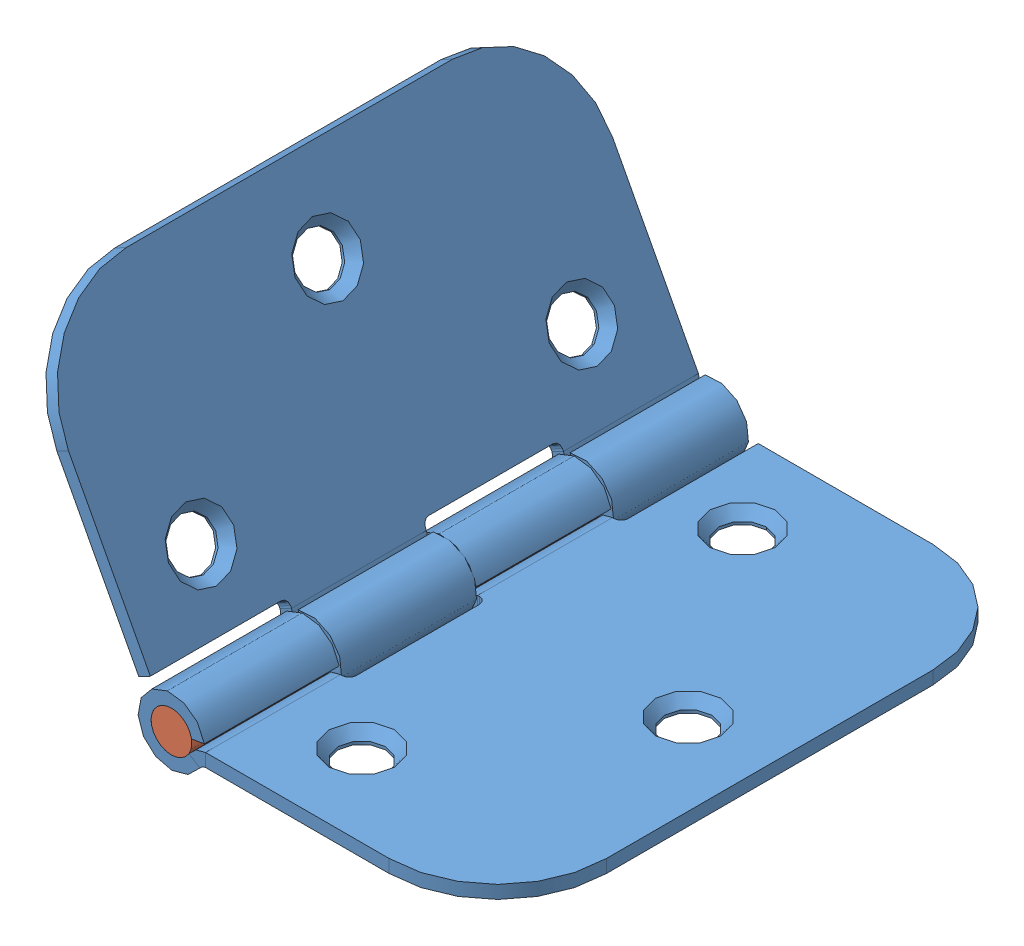
SolidWorks assembly Hinge_01, configuration Default. Lengths in mm.
Overall size (59.41 40.75 63.5).
3 component instances, 2 part files, 6 mates.
Components (placement in the parent):
- Hinge_01-1: Hinge_01 [Default] at origin size (42 7.8 63.5)
- Hinge_01-2: Hinge_01 [Default] at (-56.0759 33.72 -63.5) x (-0.468865 0.88327 0) z (0 0 -1) size (42 7.8 63.5)
- Hinge_01_Pin-1: Hinge_01_Pin [Default] at (-56.0759 33.72 -63.5) x (-0.468865 0.88327 0) z (0 0 -1) size (4.75 4.75 63.5)
Mates (geometry in assembly coordinates):
- Concentric1: concentric anti-aligned: cylinder of Hinge_01-1 through (-38.1 0.127 -127.7853) axis (0 0 1) radius 2.3749; cylinder of Hinge_01-2 through (-38.1 0.127 36.1195) axis (0 0 -1) radius 2.3749
- Coincident1: coincident aligned: plane of Hinge_01-1 through (-34.1123 -144.1652 -63.5) normal (0 0 -1); plane of Hinge_01-2 through (-167.4186 -64.0044 -63.5) normal (0 0 -1)
- Inplace1: in place: line of ? through (-38.1 0.127 -63.5) axis (0 0 -1); line of ? through (-57.6566 32.8251 -63.5) axis (0 0 -1); moOrthogonalPlaneRef_w of ? through (-38.1 0.127 -63.5) axis (0 0 -1); line of ? through (-57.6566 32.8251 -63.5) axis (0.859919 0.510431 0); line of ? through (-38.1 0.127 -63.5) axis (0 0 -1); line of ? through (-57.6566 32.8251 -63.5) axis (-0.510431 0.859919 0); plane of ? through (-38.1 0.127 -63.5) normal (0 0 -1); unknown of ?
- Coincident2: coincident aligned: plane of Hinge_01-2; plane of Hinge_01_Pin-1
- Coincident3: coincident aligned: moOrthogonalPlaneRef_w of Hinge_01-2 through (-56.0759 33.72 -63.5) axis (0.88327 0.468865 0); plane of Hinge_01_Pin-1
- Coincident4: coincident anti-aligned: moOrthogonalPlaneRef_w of Hinge_01-2 through (-56.0759 33.72 -63.5) axis (0.468865 -0.88327 0); plane of Hinge_01_Pin-1
